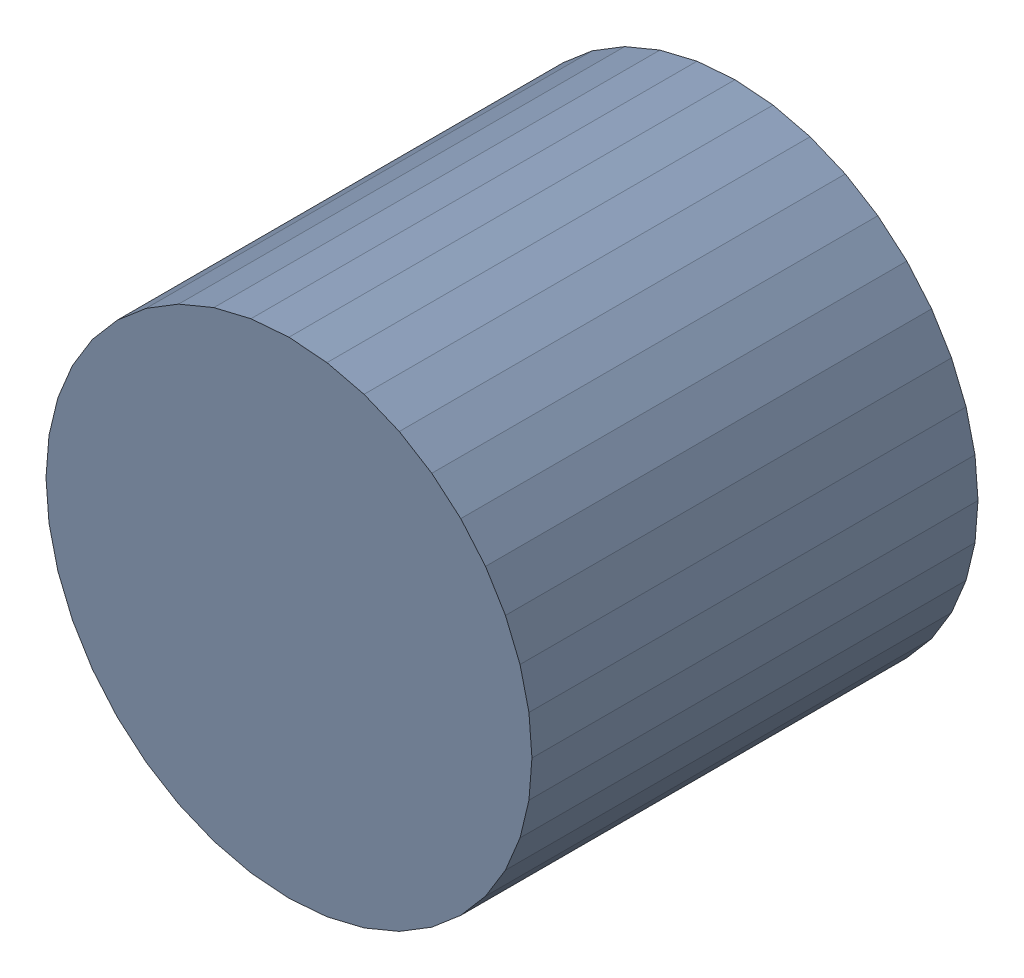
SolidWorks assembly C10_Motor_7Kanaloa_v2.0.0_Motor, configuration Default. Lengths in mm.
Overall size (6.32 6.32 5.8).
2 component instances, 1 part files, 0 mates.
Components (placement in the parent):
- 352892112-1: 352892112 [Default] at (88.836 127 0) size (6.32 6.32 5.8)
  - Extruded_11-1: Extruded_11 [Default] at origin size (6.32 6.32 5.8)
